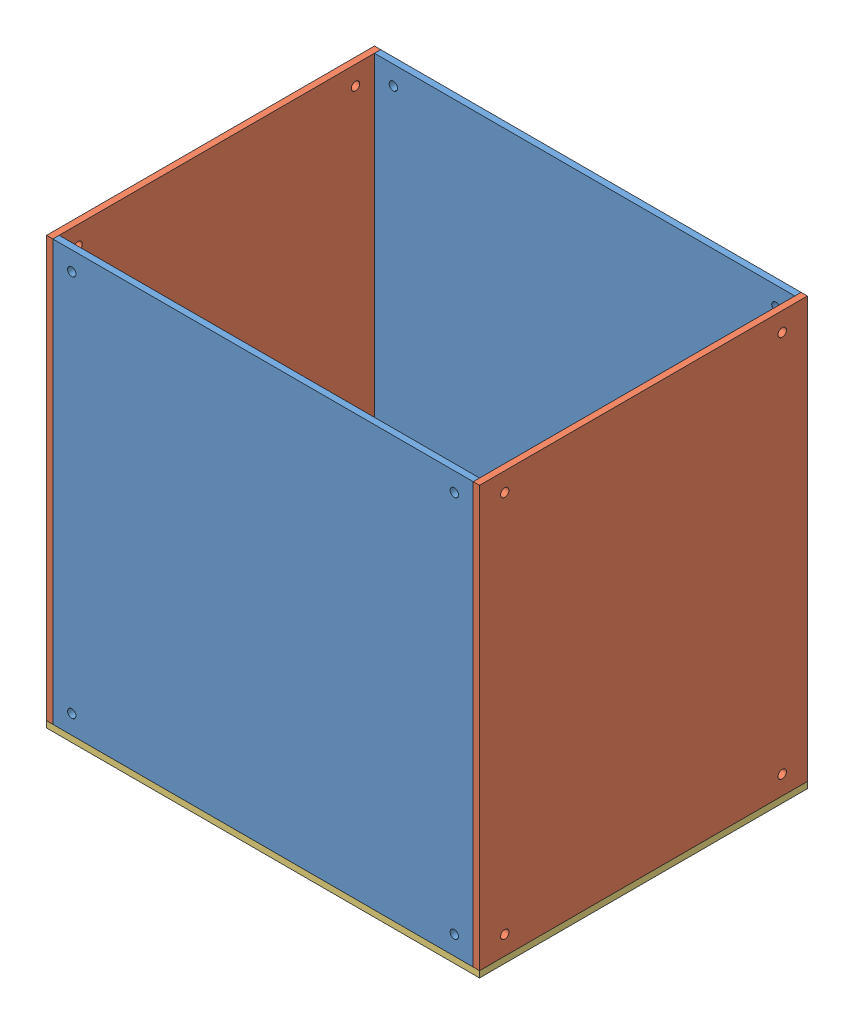
SolidWorks assembly 2018_bee_box_assy, configuration Défaut. Lengths in mm.
Overall size (206 203 156).
6 component instances, 4 part files, 14 mates.
Components (placement in the parent):
- 2018_bee_box_1-1: 2018_bee_box_1 [Défaut] at (-103.1128 -107.374 -1.5) size (200 200 3)
- 2018_bee_box_2-1: 2018_bee_box_2 [Défaut] at (-106.1128 -107.374 1.5) x (0 0 -1) z (1 0 0) size (156 200 3)
- 2018_bee_box_1-2: 2018_bee_box_1 [Défaut] at (-103.1128 -107.374 -154.5) size (200 200 3)
- 2018_bee_box_2-2: 2018_bee_box_2 [Défaut] at (96.8872 -107.374 1.5) x (0 0 -1) z (1 0 0) size (156 200 3)
- 2018_bee_box_3-1: 2018_bee_box_3 [Défaut] at (99.8872 -110.374 -154.5) x (-1 0 0) z (0 1 0) size (206 156 3)
- 2018_bee_box_square-1: 2018_bee_box_square [Défaut] at (-103.1128 -107.374 -21.5) size (20 20 20)
Mates (geometry in assembly coordinates):
- Coïncidente1: coincident aligned: plane of 2018_bee_box_1-1 through (-103.1128 -107.374 1.5) normal (0 0 1); plane of 2018_bee_box_2-1 through (-103.1128 -107.374 1.5) normal (0 0 1)
- Coïncidente2: coincident anti-aligned: plane of 2018_bee_box_1-1 through (-103.1128 -107.374 1.5) normal (-1 0 0); plane of 2018_bee_box_2-1 through (-103.1128 -107.374 1.5) normal (1 0 0)
- Coïncidente3: coincident aligned: plane of 2018_bee_box_1-1 through (-103.1128 92.626 1.5) normal (0 1 0); plane of 2018_bee_box_2-1 through (-103.1128 92.626 1.5) normal (0 1 0)
- Coïncidente4: coincident aligned: plane of 2018_bee_box_2-1 through (-103.1128 -107.374 -154.5) normal (0 0 -1); plane of 2018_bee_box_1-2 through (-103.1128 -107.374 -154.5) normal (0 0 -1)
- Coïncidente5: coincident anti-aligned: plane of 2018_bee_box_2-1 through (-103.1128 -107.374 1.5) normal (1 0 0); plane of 2018_bee_box_1-2 through (-103.1128 -107.374 -151.5) normal (-1 0 0)
- Coïncidente6: coincident aligned: plane of 2018_bee_box_2-1 through (-103.1128 92.626 1.5) normal (0 1 0); plane of 2018_bee_box_1-2 through (-103.1128 92.626 -151.5) normal (0 1 0)
- Coïncidente7: coincident anti-aligned: plane of 2018_bee_box_1-1 through (96.8872 -107.374 1.5) normal (1 0 0); plane of 2018_bee_box_2-2 through (96.8872 -107.374 1.5) normal (-1 0 0)
- Coïncidente8: coincident aligned: plane of 2018_bee_box_1-1 through (-103.1128 92.626 1.5) normal (0 1 0); plane of 2018_bee_box_2-2 through (99.8872 92.626 1.5) normal (0 1 0)
- Coïncidente9: coincident aligned: plane of 2018_bee_box_1-1 through (-103.1128 -107.374 1.5) normal (0 0 1); plane of 2018_bee_box_2-2 through (99.8872 -107.374 1.5) normal (0 0 1)
- Coïncidente10: coincident anti-aligned: plane of 2018_bee_box_1-1 through (-103.1128 -107.374 1.5) normal (0 -1 0); plane of 2018_bee_box_3-1 through (99.8872 -107.374 -154.5) normal (0 1 0)
- Coïncidente11: coincident aligned: plane of 2018_bee_box_2-2 through (99.8872 -107.374 1.5) normal (1 0 0); plane of 2018_bee_box_3-1 through (99.8872 -107.374 -154.5) normal (1 0 0)
- Coïncidente12: coincident aligned: plane of 2018_bee_box_1-1 through (-103.1128 -107.374 1.5) normal (0 0 1); plane of 2018_bee_box_3-1 through (99.8872 -107.374 1.5) normal (0 0 1)
- Coaxiale1: concentric aligned: circle of 2018_bee_box_1-1; cylinder of 2018_bee_box_square-1 through (-94.1128 -98.374 -1.5) axis (0 0 -1) radius 1.75
- Coaxiale2: concentric aligned: cylinder of 2018_bee_box_2-1 through (-106.1128 -98.374 -10.5) axis (1 0 0) radius 2; cylinder of 2018_bee_box_square-1 through (-103.1129 -98.374 -10.5) axis (1 0 0) radius 1.75
